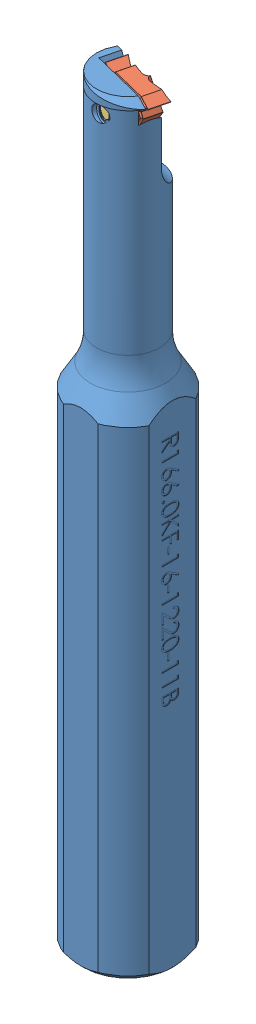
SolidWorks assembly Suporte Rosca, configuration Valor predeterminado. Lengths in mm.
Overall size (16.86 123.8 15.02).
3 component instances, 3 part files, 5 mates.
Components (placement in the parent):
- Suporte Rosca-1: Suporte Rosca [Valor predeterminado] at (6.9327 -60.6062 120) size (15.07 120 15.02)
- Pastilha Rosca 11mm-1: Pastilha Rosca 11mm [Valor predeterminado] at (8.1504 56.2184 121.8495) x (-0.485148 0.866025 -0.120961) z (0.241922 0 -0.970296) size (9.39 8.59 3.2)
- M2.5-1: M2.5 [Valor predeterminado] at (7.5426 56.2184 124.2872) x (0.348051 0.933451 0.086779) z (-0.905723 0.358706 -0.225822) size (3.6 6.14 3.6)
Mates (geometry in assembly coordinates):
- Coincidente1: coincident aligned: plane of Suporte Rosca-1 through (11.9327 59.3938 120) normal (0 1 0); plane of Pastilha Rosca 11mm-1 through (14.2611 59.3938 120.0751) normal (0 1 0)
- Distância1: distance = 0.2 mm aligned: plane of Pastilha Rosca 11mm-1 through (8.9245 56.2184 118.7446) normal (0.241922 0 -0.970296); plane of Suporte Rosca-1 through (1.1003 44.3938 116.9999) normal (0.241922 0 -0.970296)
- Concêntrico1: concentric aligned: cylinder of M2.5-1 through (7.5426 56.2184 124.2872) axis (-0.241922 0 0.970296) radius 1.8; cylinder of Pastilha Rosca 11mm-1 through (8.1504 56.2184 121.8495) axis (-0.241922 0 0.970296) radius 1.9
- Coincidente2: coincident anti-aligned: circle of Pastilha Rosca 11mm-1; cone of M2.5-1 through (8.4861 56.2184 120.5031) axis (-0.241922 0 0.970296)
- Paralelo1: parallel: line of Suporte Rosca-1 through (2.6676 48.3938 117.3907) axis (0 1 0); plane of M2.5-1 through (9.6036 56.2184 119.648) normal (-0.970296 0 -0.241922)
